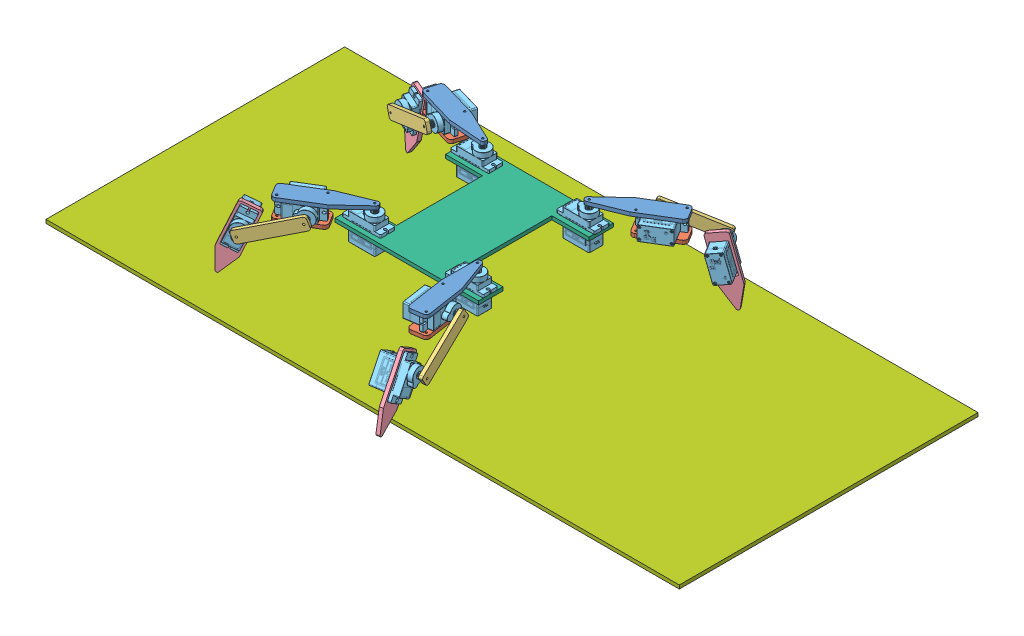
SolidWorks assembly Braço, configuration Default. Lengths in mm.
Overall size (530 83.15 285.34).
30 component instances, 7 part files, 82 mates.
Components (placement in the parent):
- Peça2-1: Peça2 [Default] at (-104.7951 66.2529 157.6687) x (0 -1 0) z (-0.85285 0 0.522157) size (3 15 64.39)
- Peça3-1: Peça3 [Default] at (-112.3154 51.0529 162.273) x (0 -1 0) z (-0.85285 0 0.522157) size (3 15 35)
- Peça4-1: Peça4 [Default] at (-116.1008 49.2129 185.5205) x (-0.522157 0 -0.85285) z (0.795367 0.360912 -0.486963) size (3 10 50)
- Peça5-1: Peça5 [Default] at (-146.1936 35.3525 180.3181) x (0.522157 0 0.85285) z (-0.788928 0.379846 0.483021) size (3 55.59 16)
- SG90 - Micro Servo 9g - Tower Pro.1-1: SG90 - Micro Servo 9g - Tower Pro.1 [Peça] at (-114.639 57.1529 158.4778) x (-0.85285 0 0.522157) z (0 1 0) size (32.1 29.95 12.4)
- SG90 - Micro Servo 9g - Tower Pro.1-2: SG90 - Micro Servo 9g - Tower Pro.1 [Peça] at (-146.9113 36.5088 178.2366) x (-0.323952 -0.92505 0.198339) z (-0.788928 0.379846 0.483021) size (32.1 29.95 12.4)
- SG90 - Micro Servo 9g - Tower Pro.1-3: SG90 - Micro Servo 9g - Tower Pro.1 [Peça] at (-80.4063 43.9529 138.7398) x (-1 0 0) z (0 0 -1) size (32.1 29.95 12.4)
- Base-1: Base [Default] at (-38.1563 46.1029 92.6398) x (1 0 0) z (0 1 0) size (120 112.8 3)
- Peça2-2: Peça2 [Default] at (-110.8287 66.2529 37.4019) x (0 -1 0) z (-0.959938 0 -0.280211) size (3 15 64.39)
- Peça3-2: Peça3 [Default] at (-119.2933 51.0529 34.931) x (0 -1 0) z (-0.959938 0 -0.280211) size (3 15 35)
- Peça4-2: Peça4 [Default] at (-139.1102 49.3862 47.7413) x (0.280211 0 -0.959938) z (0.898129 0.353033 0.262169) size (3 10 50)
- Peça5-2: Peça5 [Default] at (-154.8644 35.4522 22.1516) x (-0.280211 0 0.959938) z (-0.925035 0.267204 -0.270023) size (3 55.59 16)
- SG90 - Micro Servo 9g - Tower Pro.1-4: SG90 - Micro Servo 9g - Tower Pro.1 [Peça] at (-118.0464 57.1529 30.6593) x (-0.959938 0 -0.280211) z (0 1 0) size (32.1 29.95 12.4)
- SG90 - Micro Servo 9g - Tower Pro.1-5: SG90 - Micro Servo 9g - Tower Pro.1 [Peça] at (-153.9413 36.6568 20.1814) x (-0.256499 -0.96364 -0.074874) z (-0.925035 0.267204 -0.270023) size (32.1 29.95 12.4)
- SG90 - Micro Servo 9g - Tower Pro.1-6: SG90 - Micro Servo 9g - Tower Pro.1 [Peça] at (-82.1063 43.9529 46.5398) x (-1 0 0) z (0 0 -1) size (32.1 29.95 12.4)
- Peça2-3: Peça2 [Default] at (16.9251 66.2529 173.5096) x (0 -1 0) z (0.150244 0 0.988649) size (3 15 64.39)
- Peça3-3: Peça3 [Default] at (18.2499 51.0529 182.2274) x (0 -1 0) z (0.150244 0 0.988649) size (3 15 35)
- Peça4-3: Peça4 [Default] at (37.8871 45.0831 192.6386) x (-0.988649 0 0.150244) z (-0.125613 0.548631 -0.826574) size (3 10 50)
- Peça5-3: Peça5 [Default] at (21.2434 27.605 217.234) x (0.988649 0 -0.150244) z (0.126961 0.534715 0.835441) size (3 55.59 16)
- SG90 - Micro Servo 9g - Tower Pro.1-7: SG90 - Micro Servo 9g - Tower Pro.1 [Peça] at (13.8505 57.1529 182.8959) x (0.150244 0 0.988649) z (0 1 0) size (32.1 29.95 12.4)
- SG90 - Micro Servo 9g - Tower Pro.1-8: SG90 - Micro Servo 9g - Tower Pro.1 [Peça] at (19.0174 28.6613 216.8962) x (0.080338 -0.845033 0.528645) z (0.126961 0.534715 0.835441) size (32.1 29.95 12.4)
- SG90 - Micro Servo 9g - Tower Pro.1-9: SG90 - Micro Servo 9g - Tower Pro.1 [Peça] at (5.7937 43.9529 138.9398) x (-1 0 0) z (0 0 -1) size (32.1 29.95 12.4)
- Peça2-4: Peça2 [Default] at (41.3082 66.2529 27.451) x (0 -1 0) z (0.853556 0 -0.521001) size (3 15 64.39)
- Peça3-4: Peça3 [Default] at (48.8347 51.0529 22.8569) x (0 -1 0) z (0.853556 0 -0.521001) size (3 15 35)
- Peça4-4: Peça4 [Default] at (53.0666 50.6063 -0.6387) x (0.521001 0 0.853556) z (-0.814888 0.297576 0.497399) size (3 10 50)
- Peça5-4: Peça5 [Default] at (82.8317 37.855 4.8001) x (-0.521001 0 -0.853556) z (0.8275 0.245195 -0.505097) size (3 55.59 16)
- SG90 - Micro Servo 9g - Tower Pro.1-10: SG90 - Micro Servo 9g - Tower Pro.1 [Peça] at (51.1532 57.1529 26.6552) x (0.853556 0 -0.521001) z (0 1 0) size (32.1 29.95 12.4)
- SG90 - Micro Servo 9g - Tower Pro.1-11: SG90 - Micro Servo 9g - Tower Pro.1 [Peça] at (83.6903 39.0668 6.7949) x (0.209288 -0.969474 -0.127747) z (0.8275 0.245195 -0.505097) size (32.1 29.95 12.4)
- SG90 - Micro Servo 9g - Tower Pro.1-12: SG90 - Micro Servo 9g - Tower Pro.1 [Peça] at (6.5937 43.9529 46.3398) x (-1 0 0) z (0 0 -1) size (32.1 29.95 12.4)
- chao-1: chao [Valor predeterminado] at (-16.2183 -16.8971 82.9208) x (1 0 0) z (0 1 0) size (530 250 3)
Mates (geometry in assembly coordinates):
- Coincidente1: coincident anti-aligned: plane of Peça2-1 through (-74.0971 63.2529 138.718) normal (0 -1 0); plane of SG90 - Micro Servo 9g - Tower Pro.1-1 through (-129.0174 63.2529 154.9107) normal (0 1 0)
- Concêntrico1: concentric aligned: circle of Peça2-1; circle of Peça3-1
- Concêntrico2: concentric anti-aligned: cylinder of Peça2-1 through (-102.2988 63.2529 150.8639) axis (0 1 0) radius 0.8; circle of Peça3-1
- Coincidente9: coincident anti-aligned: plane of Peça3-1 through (-112.3154 51.0529 162.273) normal (0 1 0); plane of SG90 - Micro Servo 9g - Tower Pro.1-1 through (-111.2781 51.0529 144.0498) normal (0 -1 0)
- Coincidente11: coincident anti-aligned: circle of Peça4-1; circle of SG90 - Micro Servo 9g - Tower Pro.1-1
- Distância1: distance = 6.25 mm aligned: plane of SG90 - Micro Servo 9g - Tower Pro.1-1 through (-121.5444 62.4029 168.7443) normal (-0.85285 0 0.522157); plane of Peça3-1 through (-123.3241 48.0529 177.8071) normal (-0.85285 0 0.522157)
- Concêntrico4: concentric anti-aligned: circle of Peça2-1; circle of SG90 - Micro Servo 9g - Tower Pro.1-3
- Paralelo4: parallel anti-aligned: plane of Peça5-1 through (-153.5679 26.1444 188.3506) normal (0.323952 0.92505 -0.198339); plane of SG90 - Micro Servo 9g - Tower Pro.1-2 through (-151.9227 24.1078 168.9345) normal (-0.323952 -0.92505 0.198339)
- Paralelo5: parallel aligned: plane of Peça5-1 through (-135.6864 44.5606 177.4027) normal (-0.788928 0.379846 0.483021); plane of SG90 - Micro Servo 9g - Tower Pro.1-2 through (-160.6016 29.2054 174.2482) normal (-0.788928 0.379846 0.483021)
- Coincidente19: coincident anti-aligned: plane of Peça5-1 through (-156.4116 2.5486 190.0917) normal (0.522157 0 0.85285); plane of SG90 - Micro Servo 9g - Tower Pro.1-2 through (-143.44 52.5638 182.1498) normal (-0.522157 0 -0.85285)
- Coincidente20: coincident anti-aligned: plane of Peça5-1 through (-145.4691 49.2707 183.3921) normal (-0.323952 -0.92505 0.198339); plane of SG90 - Micro Servo 9g - Tower Pro.1-2 through (-144.7196 48.9098 182.9333) normal (0.323952 0.92505 -0.198339)
- Distância4: distance = 0.1 mm anti-aligned: plane of Peça5-1 through (-135.6864 44.5606 177.4027) normal (-0.788928 0.379846 0.483021); plane of SG90 - Micro Servo 9g - Tower Pro.1-2 through (-144.2385 43.8123 164.2298) normal (0.788928 -0.379846 -0.483021)
- Coincidente26: coincident anti-aligned: plane of Peça2-1 through (-74.0971 63.2529 138.718) normal (0 -1 0); plane of SG90 - Micro Servo 9g - Tower Pro.1-3 through (-75.2563 63.2529 138.7398) normal (0 1 0)
- Concêntrico7: concentric anti-aligned: circle of Peça4-1; circle of SG90 - Micro Servo 9g - Tower Pro.1-2
- Coincidente28: coincident anti-aligned: plane of Peça4-1 through (-117.6673 49.2129 182.9619) normal (-0.522157 0 -0.85285); plane of SG90 - Micro Servo 9g - Tower Pro.1-2 through (-135.1654 41.2728 193.6751) normal (0.522157 0 0.85285)
- Coincidente29: coincident anti-aligned: plane of SG90 - Micro Servo 9g - Tower Pro.1-3 through (-65.2063 49.1029 133.4898) normal (0 -1 0); plane of Base-1 through (-38.1563 49.1029 92.6398) normal (0 1 0)
- Coincidente31: coincident anti-aligned: plane of SG90 - Micro Servo 9g - Tower Pro.1-3 through (-69.1563 49.1029 133.4898) normal (1 0 0); plane of Base-1 through (-69.1563 49.1029 145.0398) normal (-1 0 0)
- Coincidente32: coincident anti-aligned: plane of SG90 - Micro Servo 9g - Tower Pro.1-3 through (-70.0063 49.1029 132.6398) normal (0 0 -1); plane of Base-1 through (-69.1563 49.1029 132.6398) normal (0 0 1)
- Coincidente33: coincident aligned: plane of Peça2-1 through (-123.3241 63.2529 177.8071) normal (0.522157 0 0.85285); plane of SG90 - Micro Servo 9g - Tower Pro.1-1 through (-99.5296 62.4029 163.239) normal (0.522157 0 0.85285)
- Coincidente34: coincident anti-aligned: plane of Peça2-2 through (-76.1607 63.2529 47.3831) normal (0 -1 0); plane of SG90 - Micro Servo 9g - Tower Pro.1-4 through (-125.0735 63.2529 17.6178) normal (0 1 0)
- Coincidente35: coincident anti-aligned: circle of Peça4-2; circle of SG90 - Micro Servo 9g - Tower Pro.1-4
- Coincidente36: coincident anti-aligned: plane of Peça4-2 through (-138.2696 49.3862 44.8615) normal (0.280211 0 -0.959938); plane of SG90 - Micro Servo 9g - Tower Pro.1-5 through (-158.0284 41.6195 39.0938) normal (-0.280211 0 0.959938)
- Coincidente37: coincident anti-aligned: plane of Peça3-2 through (-119.2933 51.0529 34.931) normal (0 1 0); plane of SG90 - Micro Servo 9g - Tower Pro.1-4 through (-105.1068 51.0529 23.4462) normal (0 -1 0)
- Coincidente38: coincident anti-aligned: plane of Peça5-2 through (-165.1323 1.2385 22.2796) normal (-0.280211 0 0.959938); plane of SG90 - Micro Servo 9g - Tower Pro.1-5 through (-156.3421 52.7069 24.8455) normal (0.280211 0 -0.959938)
- Coincidente39: coincident anti-aligned: plane of Peça5-2 through (-158.234 49.1544 24.2932) normal (-0.256499 -0.96364 -0.074874); plane of SG90 - Micro Servo 9g - Tower Pro.1-5 through (-157.3552 48.9005 24.5498) normal (0.256499 0.96364 0.074874)
- Coincidente40: coincident aligned: plane of Peça2-2 through (-138.1938 63.2529 37.2269) normal (-0.280211 0 0.959938); plane of SG90 - Micro Servo 9g - Tower Pro.1-4 through (-111.4115 62.4029 45.0448) normal (-0.280211 0 0.959938)
- Paralelo6: parallel aligned: plane of Peça5-2 through (-146.7636 45.841 27.6415) normal (-0.925035 0.267204 -0.270023); plane of SG90 - Micro Servo 9g - Tower Pro.1-5 through (-159.2954 28.2648 7.6282) normal (-0.925035 0.267204 -0.270023)
- Paralelo7: parallel anti-aligned: plane of Peça5-2 through (-164.6465 25.0634 22.4214) normal (0.256499 0.96364 0.074874); plane of SG90 - Micro Servo 9g - Tower Pro.1-5 through (-149.0143 24.413 10.6293) normal (-0.256499 -0.96364 -0.074874)
- Coincidente41: coincident anti-aligned: plane of Peça2-2 through (-76.1607 63.2529 47.3831) normal (0 -1 0); plane of SG90 - Micro Servo 9g - Tower Pro.1-6 through (-76.9563 63.2529 46.5398) normal (0 1 0)
- Concêntrico8: concentric anti-aligned: cylinder of Peça2-2 through (-104.1133 63.2529 34.6744) axis (0 1 0) radius 0.8; circle of Peça3-2
- Concêntrico9: concentric anti-aligned: circle of Peça2-2; circle of SG90 - Micro Servo 9g - Tower Pro.1-6
- Concêntrico10: concentric aligned: circle of Peça2-2; circle of Peça3-2
- Concêntrico11: concentric anti-aligned: circle of Peça4-2; circle of SG90 - Micro Servo 9g - Tower Pro.1-5
- Distância5: distance = 0.1 mm anti-aligned: plane of Peça5-2 through (-146.7636 45.841 27.6415) normal (-0.925035 0.267204 -0.270023); plane of SG90 - Micro Servo 9g - Tower Pro.1-5 through (-142.6748 45.0487 12.4798) normal (0.925035 -0.267204 0.270023)
- Distância6: distance = 6.25 mm aligned: plane of SG90 - Micro Servo 9g - Tower Pro.1-4 through (-130.2888 62.4029 32.4506) normal (-0.959938 0 -0.280211); plane of Peça3-2 through (-138.1938 48.0529 37.2269) normal (-0.959938 0 -0.280211)
- Paralelo8: parallel anti-aligned: plane of Base-1 through (-38.1563 49.1029 92.6398) normal (0 1 0); plane of SG90 - Micro Servo 9g - Tower Pro.1-6 through (-66.9063 49.1029 41.2898) normal (0 -1 0)
- Coincidente43: coincident anti-aligned: plane of Base-1 through (-38.1563 49.1029 92.6398) normal (0 1 0); plane of SG90 - Micro Servo 9g - Tower Pro.1-6 through (-66.9063 49.1029 41.2898) normal (0 -1 0)
- Paralelo9: parallel aligned: plane of Base-1 through (-98.1563 49.1029 36.2398) normal (0 0 -1); plane of SG90 - Micro Servo 9g - Tower Pro.1-6 through (-66.9063 51.6029 40.4398) normal (0 0 -1)
- Coincidente45: coincident aligned: plane of Base-1 through (-98.1563 49.1029 36.2398) normal (-1 0 0); plane of SG90 - Micro Servo 9g - Tower Pro.1-6 through (-98.1563 51.6029 41.2898) normal (-1 0 0)
- Coincidente46: coincident anti-aligned: plane of Peça2-3 through (11.3734 63.2529 137.863) normal (0 -1 0); plane of SG90 - Micro Servo 9g - Tower Pro.1-7 through (4.9827 63.2529 194.763) normal (0 1 0)
- Coincidente47: coincident anti-aligned: circle of Peça4-3; circle of SG90 - Micro Servo 9g - Tower Pro.1-7
- Coincidente48: coincident anti-aligned: plane of Peça4-3 through (34.9211 45.0831 193.0893) normal (-0.988649 0 0.150244); plane of SG90 - Micro Servo 9g - Tower Pro.1-8 through (37.6846 33.0132 211.274) normal (0.988649 0 -0.150244)
- Coincidente49: coincident anti-aligned: plane of Peça3-3 through (18.2499 51.0529 182.2274) normal (0 1 0); plane of SG90 - Micro Servo 9g - Tower Pro.1-7 through (1.8577 51.0529 174.1991) normal (0 -1 0)
- Coincidente50: coincident anti-aligned: plane of Peça5-3 through (27.1097 -2.301 235.8685) normal (0.988649 0 -0.150244); plane of SG90 - Micro Servo 9g - Tower Pro.1-8 through (23.5544 44.313 212.4731) normal (-0.988649 0 0.150244)
- Coincidente51: coincident anti-aligned: plane of Peça5-3 through (23.9923 41.4831 215.3549) normal (0.080338 -0.845033 0.528645); plane of SG90 - Micro Servo 9g - Tower Pro.1-8 through (23.8717 40.9751 214.5612) normal (-0.080338 0.845033 -0.528645)
- Coincidente52: coincident aligned: plane of Peça2-3 through (28.2941 63.2529 198.4019) normal (0.988649 0 -0.150244); plane of SG90 - Micro Servo 9g - Tower Pro.1-7 through (24.1023 62.4029 170.8186) normal (0.988649 0 -0.150244)
- Paralelo10: parallel aligned: plane of Peça5-3 through (22.418 34.8526 204.9955) normal (0.126961 0.534715 0.835441); plane of SG90 - Micro Servo 9g - Tower Pro.1-8 through (10.1972 23.1347 229.0754) normal (0.126961 0.534715 0.835441)
- Paralelo11: parallel anti-aligned: plane of Peça5-3 through (26.0008 20.3573 228.571) normal (-0.080338 0.845033 -0.528645); plane of SG90 - Micro Servo 9g - Tower Pro.1-8 through (8.8244 16.3474 220.0425) normal (0.080338 -0.845033 0.528645)
- Coincidente53: coincident anti-aligned: plane of Peça2-3 through (11.3734 63.2529 137.863) normal (0 -1 0); plane of SG90 - Micro Servo 9g - Tower Pro.1-9 through (10.9437 63.2529 138.9398) normal (0 1 0)
- Concêntrico12: concentric anti-aligned: cylinder of Peça2-3 through (11.6225 63.2529 168.568) axis (0 1 0) radius 0.8; circle of Peça3-3
- Concêntrico13: concentric anti-aligned: circle of Peça2-3; circle of SG90 - Micro Servo 9g - Tower Pro.1-9
- Concêntrico14: concentric aligned: circle of Peça2-3; circle of Peça3-3
- Concêntrico15: concentric anti-aligned: circle of Peça4-3; circle of SG90 - Micro Servo 9g - Tower Pro.1-8
- Distância7: distance = 0.1 mm anti-aligned: plane of Peça5-3 through (22.418 34.8526 204.9955) normal (0.126961 0.534715 0.835441); plane of SG90 - Micro Servo 9g - Tower Pro.1-8 through (6.9772 34.1878 207.8872) normal (-0.126961 -0.534715 -0.835441)
- Distância8: distance = 6.25 mm aligned: plane of SG90 - Micro Servo 9g - Tower Pro.1-7 through (20.6322 62.4029 193.2445) normal (0.150244 0 0.988649); plane of Peça3-3 through (28.2941 48.0529 198.4019) normal (0.150244 0 0.988649)
- Paralelo12: parallel aligned: plane of Base-1 through (-9.1563 49.1029 128.6398) normal (0 0 -1); plane of SG90 - Micro Servo 9g - Tower Pro.1-9 through (20.9937 51.6029 132.8398) normal (0 0 -1)
- Coincidente55: coincident aligned: plane of Base-1 through (21.8437 49.1029 128.6398) normal (1 0 0); plane of SG90 - Micro Servo 9g - Tower Pro.1-9 through (21.8437 51.6029 133.6898) normal (1 0 0)
- Coincidente56: coincident anti-aligned: plane of Base-1 through (-38.1563 49.1029 92.6398) normal (0 1 0); plane of SG90 - Micro Servo 9g - Tower Pro.1-9 through (20.9937 49.1029 133.6898) normal (0 -1 0)
- Simétrico1: symmetric anti-aligned: plane of Base-1 through (-7.1563 49.1029 145.0398) normal (0 0 -1); plane of SG90 - Micro Servo 9g - Tower Pro.1-9 through (20.9937 51.6029 145.0398) normal (0 0 1); plane of Peça2-3 through (11.3734 66.2529 137.863) normal (0 1 0)
- Coincidente58: coincident anti-aligned: plane of Base-1 through (-69.1563 49.1029 52.6398) normal (0 0 -1); plane of SG90 - Micro Servo 9g - Tower Pro.1-6 through (-66.9063 51.6029 52.6398) normal (0 0 1)
- Coincidente59: coincident anti-aligned: plane of Peça2-4 through (10.5846 63.2529 46.3601) normal (0 -1 0); plane of SG90 - Micro Servo 9g - Tower Pro.1-10 through (65.5267 63.2529 30.2418) normal (0 1 0)
- Coincidente60: coincident anti-aligned: circle of Peça4-4; circle of SG90 - Micro Servo 9g - Tower Pro.1-10
- Coincidente61: coincident anti-aligned: plane of Peça4-4 through (54.6296 50.6063 1.9219) normal (0.521001 0 0.853556); plane of SG90 - Micro Servo 9g - Tower Pro.1-11 through (72.5571 44.0596 -9.0208) normal (-0.521001 0 -0.853556)
- Coincidente62: coincident anti-aligned: plane of Peça3-4 through (48.8347 51.0529 22.8569) normal (0 1 0); plane of SG90 - Micro Servo 9g - Tower Pro.1-10 through (47.7727 51.0529 41.0786) normal (0 -1 0)
- Coincidente63: coincident anti-aligned: plane of Peça5-4 through (88.9842 3.4266 -2.4701) normal (-0.521001 0 -0.853556); plane of SG90 - Micro Servo 9g - Tower Pro.1-11 through (82.1703 55.0901 1.6891) normal (0.521001 0 0.853556)
- Coincidente64: coincident anti-aligned: plane of Peça5-4 through (83.7831 51.4936 0.7046) normal (0.209288 -0.969474 -0.127747); plane of SG90 - Micro Servo 9g - Tower Pro.1-11 through (82.997 51.2607 1.1845) normal (-0.209288 0.969474 0.127747)
- Coincidente65: coincident aligned: plane of Peça2-4 through (59.8644 63.2529 7.3377) normal (-0.521001 0 -0.853556); plane of SG90 - Micro Servo 9g - Tower Pro.1-10 through (36.0502 62.4029 21.8736) normal (-0.521001 0 -0.853556)
- Paralelo13: parallel aligned: plane of Peça5-4 through (73.5221 48.4532 6.9678) normal (0.8275 0.245195 -0.505097); plane of SG90 - Micro Servo 9g - Tower Pro.1-11 through (96.4112 30.48 11.3902) normal (0.8275 0.245195 -0.505097)
- Paralelo14: parallel anti-aligned: plane of Peça5-4 through (89.0153 27.2568 -2.489) normal (-0.209288 0.969474 0.127747); plane of SG90 - Micro Servo 9g - Tower Pro.1-11 through (87.1969 26.873 17.0145) normal (0.209288 -0.969474 -0.127747)
- Coincidente66: coincident anti-aligned: plane of Peça2-4 through (10.5846 63.2529 46.3601) normal (0 -1 0); plane of SG90 - Micro Servo 9g - Tower Pro.1-12 through (11.7437 63.2529 46.3398) normal (0 1 0)
- Concêntrico16: concentric anti-aligned: cylinder of Peça2-4 through (38.8027 63.2529 34.2524) axis (0 1 0) radius 0.8; circle of Peça3-4
- Concêntrico17: concentric anti-aligned: circle of Peça2-4; circle of SG90 - Micro Servo 9g - Tower Pro.1-12
- Concêntrico18: concentric aligned: circle of Peça2-4; circle of Peça3-4
- Concêntrico19: concentric anti-aligned: circle of Peça4-4; circle of SG90 - Micro Servo 9g - Tower Pro.1-11
- Distância9: distance = 0.1 mm anti-aligned: plane of Peça5-4 through (73.5221 48.4532 6.9678) normal (0.8275 0.245195 -0.505097); plane of SG90 - Micro Servo 9g - Tower Pro.1-11 through (81.9625 47.6537 20.2096) normal (-0.8275 -0.245195 0.505097)
- Distância10: distance = 6.25 mm aligned: plane of SG90 - Micro Servo 9g - Tower Pro.1-10 through (58.0725 62.4029 16.3981) normal (0.853556 0 -0.521001); plane of Peça3-4 through (59.8644 48.0529 7.3377) normal (0.853556 0 -0.521001)
- Paralelo16: parallel aligned: plane of Base-1 through (21.8437 49.1029 36.2398) normal (1 0 0); plane of SG90 - Micro Servo 9g - Tower Pro.1-12 through (22.6437 51.6029 41.0898) normal (1 0 0)
- Coincidente71: coincident anti-aligned: plane of Base-1 through (-7.1563 49.1029 40.2398) normal (0 0 1); plane of SG90 - Micro Servo 9g - Tower Pro.1-12 through (21.7937 51.6029 40.2398) normal (0 0 -1)
- Coincidente72: coincident anti-aligned: plane of Base-1 through (-38.1563 49.1029 92.6398) normal (0 1 0); plane of SG90 - Micro Servo 9g - Tower Pro.1-12 through (21.7937 49.1029 41.0898) normal (0 -1 0)
- Coincidente73: coincident anti-aligned: plane of Base-1 through (17.8437 49.1029 40.2398) normal (-1 0 0); plane of SG90 - Micro Servo 9g - Tower Pro.1-12 through (17.8437 49.1029 41.0898) normal (1 0 0)
- Paralelo17: parallel anti-aligned: plane of Base-1 through (-38.1563 46.1029 92.6398) normal (0 -1 0); plane of chao-1 through (-16.2183 -13.8971 82.9208) normal (0 1 0)
- Distância11: distance = 60 mm anti-aligned: plane of Base-1 through (-38.1563 46.1029 92.6398) normal (0 -1 0); plane of chao-1 through (-16.2183 -13.8971 82.9208) normal (0 1 0)
